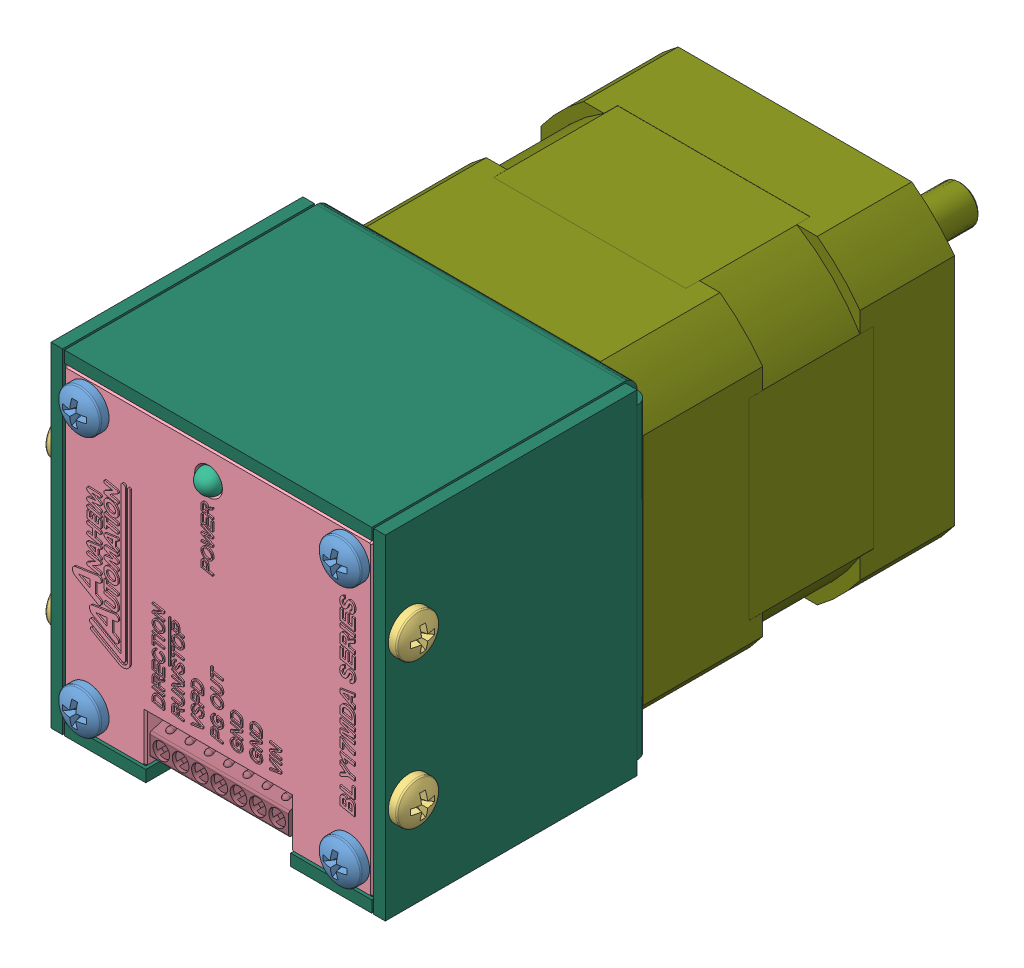
SolidWorks assembly BLY17MDA Series, configuration Default. Lengths in mm.
Overall size (48.3 43.99 99.92).
37 component instances, 19 part files, 0 mates.
Components (placement in the parent):
- 12Pan Cross Head_AI_CR-PHMS 0.112-40x0.5x0.5-S-1: 12Pan Cross Head_AI_CR-PHMS 0.112-40x0.5x0.5-S [Default] at (3.175 3.175 2.032) x (0 0 -1) z (1 0 0) size (14.86 5.56 5.64)
- Standoff, 4-40x.187_4-40 X .750-1: Standoff, 4-40x.187_4-40 X .750 [Default] at (3.175 37.465 -10.2235) size (5.5 4.76 19.05)
- 12Pan Cross Head_AI_CR-PHMS 0.112-40x0.25x0.25-S-1: 12Pan Cross Head_AI_CR-PHMS 0.112-40x0.25x0.25-S [Default] at (-3.7084 10.795 -3.175) size (8.51 5.56 5.64)
- Heat Sink, BLY17MDA Series-1: Heat Sink, BLY17MDA Series [Default] at origin size (40.64 40.64 6.53)
- Machine Screw Nut Hex_AI_MSHXNUT 0.099-56-D-S-1: Machine Screw Nut Hex_AI_MSHXNUT 0.099-56-D-S [Default] at (3.175 3.175 -11.8999) x (0.861062 0.5085 0) z (0 0 -1) size (4.78 5.51 1.68)
- AA5395-1PCB-1: AA5395-1PCB [Default] at (40.005 0.635 -10.2235) x (-1 0 0) z (0 0 -1) size (39.37 40.24 28.36)
  - LED-T-1-Series_LED-T-1-GRN-1: LED-T-1-Series_LED-T-1-GRN [Default] at (20.955 36.195 -6.1595) x (1 0 0) z (0 1 0) size (4.06 12.37 3.61)
  - CON-B5B-EH-A-1: CON-B5B-EH-A [Default] at (23.2024 12.0142 0) x (1 0 0) z (0 -1 0) size (15.24 9.17 3.81)
  - LED-LTM Series_LED-LTM180-1: LED-LTM Series_LED-LTM180 [Default] at (20.955 36.195 -2.2225) x (0 1 0) z (-1 0 0) size (5.16 4.57 5.16)
  - TRS-IRFU3607PBF with 90degree bent UP legs-1: TRS-IRFU3607PBF with 90degree bent UP legs [Default] at (14.605 12.1748 -3.8735) x (-1 0 0) z (0 1 0) size (9.78 4.95 6.53)
  - TRS-IRFU3607PBF with 90degree bent UP legs-2: TRS-IRFU3607PBF with 90degree bent UP legs [Default] at (24.765 5.656 -3.8735) x (1 0 0) z (0 -1 0) size (9.78 4.95 6.53)
  - AA5395PCB-1: AA5395PCB [Default] at origin size (39.37 39.37 1.59)
  - TRS-IRFU3607PBF with 90degree bent UP legs-3: TRS-IRFU3607PBF with 90degree bent UP legs [Default] at (14.605 33.7648 -3.8735) x (-1 0 0) z (0 1 0) size (9.78 4.95 6.53)
  - TRS-IRFU3607PBF with 90degree bent UP legs-4: TRS-IRFU3607PBF with 90degree bent UP legs [Default] at (24.765 16.451 -3.8735) x (1 0 0) z (0 -1 0) size (9.78 4.95 6.53)
  - TRS-IRFU3607PBF with 90degree bent UP legs-5: TRS-IRFU3607PBF with 90degree bent UP legs [Default] at (24.765 27.246 -3.8735) x (1 0 0) z (0 -1 0) size (9.78 4.95 6.53)
  - TRS-IRFU3607PBF with 90degree bent UP legs-6: TRS-IRFU3607PBF with 90degree bent UP legs [Default] at (14.605 22.9698 -3.8735) x (-1 0 0) z (0 1 0) size (9.78 4.95 6.53)
  - ESW-106-33-T-S_LEAD STYLE33LOCKING LEADSNonePINS6PLATINGTPOLARIZENoneROWS-1: ESW-106-33-T-S_LEAD STYLE33LOCKING LEADSNonePINS6PLATINGTPOLARIZENoneROWS [Default] at (36.8301 25.4 7.62) x (1 0 0) z (0 -1 0) size (2.54 18.42 15.75)
  - RES-3W-JAPSTYLE-1: RES-3W-JAPSTYLE [Default] at (26.3652 36.3474 12.7) x (0 0 1) z (-0.000937 -1 0) size (20.34 8.01 5.08)
  - 1725708-1: 1725708 [Default] at (24.765 23.458 4.8639) x (0 1 0) z (-1 0 0) size (6.2 12 18.24)
  - CAP-0223-1: CAP-0223 [Default] at (10.4902 34.29 0) x (-1 0 0) z (0 1 0) size (10.16 20.32 10.16)
- 12Pan Cross Head_AI_CR-PHMS 0.112-40x0.25x0.25-S-2: 12Pan Cross Head_AI_CR-PHMS 0.112-40x0.25x0.25-S [Default] at (-3.7084 29.845 -3.175) size (8.51 5.56 5.64)
- Cover, BLY17MDA Series-1: Cover, BLY17MDA Series [Default] at (42.3164 42.3164 -34.925) x (0 -1 0) z (1 0 0) size (43.99 34.92 43.99)
- Standoff, 4-40x.187_4-40 X .750-2: Standoff, 4-40x.187_4-40 X .750 [Default] at (37.465 37.465 -10.2235) size (5.5 4.76 19.05)
- 12Pan Cross Head_AI_CR-PHMS 0.112-40x0.25x0.25-S-3: 12Pan Cross Head_AI_CR-PHMS 0.112-40x0.25x0.25-S [Default] at (44.3484 10.795 -3.175) x (-1 0 0) z (0 0.999909 0.013526) size (8.51 5.56 5.64)
- Machine Screw Nut Hex_AI_MSHXNUT 0.099-56-D-S-2: Machine Screw Nut Hex_AI_MSHXNUT 0.099-56-D-S [Default] at (37.465 3.175 -11.8999) x (0.87114 0.491034 0) z (0 0 -1) size (4.78 5.51 1.68)
- 12Pan Cross Head_AI_CR-PHMS 0.112-40x0.25x0.25-S-4: 12Pan Cross Head_AI_CR-PHMS 0.112-40x0.25x0.25-S [Default] at (3.175 37.465 -32.893) x (0 0 1) z (-1 0 0) size (8.51 5.56 5.64)
- BLY171S-24V-4000-02_BLY171S-1: BLY171S-24V-4000-02_BLY171S [Default] at (20.32 20.32 -75.9206) x (0 -1 0) z (0 0 -1) size (42.01 42.01 90.14)
- AA5396-1PCB-1: AA5396-1PCB [Default] at (40.005 17.78 -30.861) x (-1 0 0) z (0 0 -1) size (39.37 22.23 11.43)
  - CON-0075-1: CON-0075 [Default] at (38.1 15.875 -1.5875) x (0 -1 0) z (0 0 -1) size (15.24 2.54 11.43)
  - AA5396PCB-1: AA5396PCB [Default] at origin size (39.37 22.23 1.59)
- 12Pan Cross Head_AI_CR-PHMS 0.112-40x0.5x0.5-S-2: 12Pan Cross Head_AI_CR-PHMS 0.112-40x0.5x0.5-S [Default] at (37.465 3.175 2.032) x (0 0 -1) z (1 0 0) size (14.86 5.56 5.64)
- 12Pan Cross Head_AI_CR-PHMS 0.112-40x0.5x0.5-S-3: 12Pan Cross Head_AI_CR-PHMS 0.112-40x0.5x0.5-S [Default] at (3.175 37.465 2.032) x (0 0 -1) z (1 0 0) size (14.86 5.56 5.64)
- Pan Cross Head_AI_CR-PHMS 0.112-40x0.188x0.188-S-1: Pan Cross Head_AI_CR-PHMS 0.112-40x0.188x0.188-S [Default] at (20.32 33.02 -31.369) x (0 0 -1) z (1 0 0) size (6.93 5.56 5.64)
- 12Pan Cross Head_AI_CR-PHMS 0.112-40x0.25x0.25-S-5: 12Pan Cross Head_AI_CR-PHMS 0.112-40x0.25x0.25-S [Default] at (37.465 37.465 -32.893) x (0 0 1) z (-1 0 0) size (8.51 5.56 5.64)
- 12Pan Cross Head_AI_CR-PHMS 0.112-40x0.5x0.5-S-4: 12Pan Cross Head_AI_CR-PHMS 0.112-40x0.5x0.5-S [Default] at (37.465 37.465 2.032) x (0 0 -1) z (1 0 0) size (14.86 5.56 5.64)
- Pan Cross Head_AI_CR-PHMS 0.112-40x0.188x0.188-S-2: Pan Cross Head_AI_CR-PHMS 0.112-40x0.188x0.188-S [Default] at (20.32 7.62 -31.369) x (0 0 -1) z (1 0 0) size (6.93 5.56 5.64)
- 12Pan Cross Head_AI_CR-PHMS 0.112-40x0.25x0.25-S-6: 12Pan Cross Head_AI_CR-PHMS 0.112-40x0.25x0.25-S [Default] at (44.3484 29.845 -3.175) x (-1 0 0) z (0 0.999976 0.006953) size (8.51 5.56 5.64)
